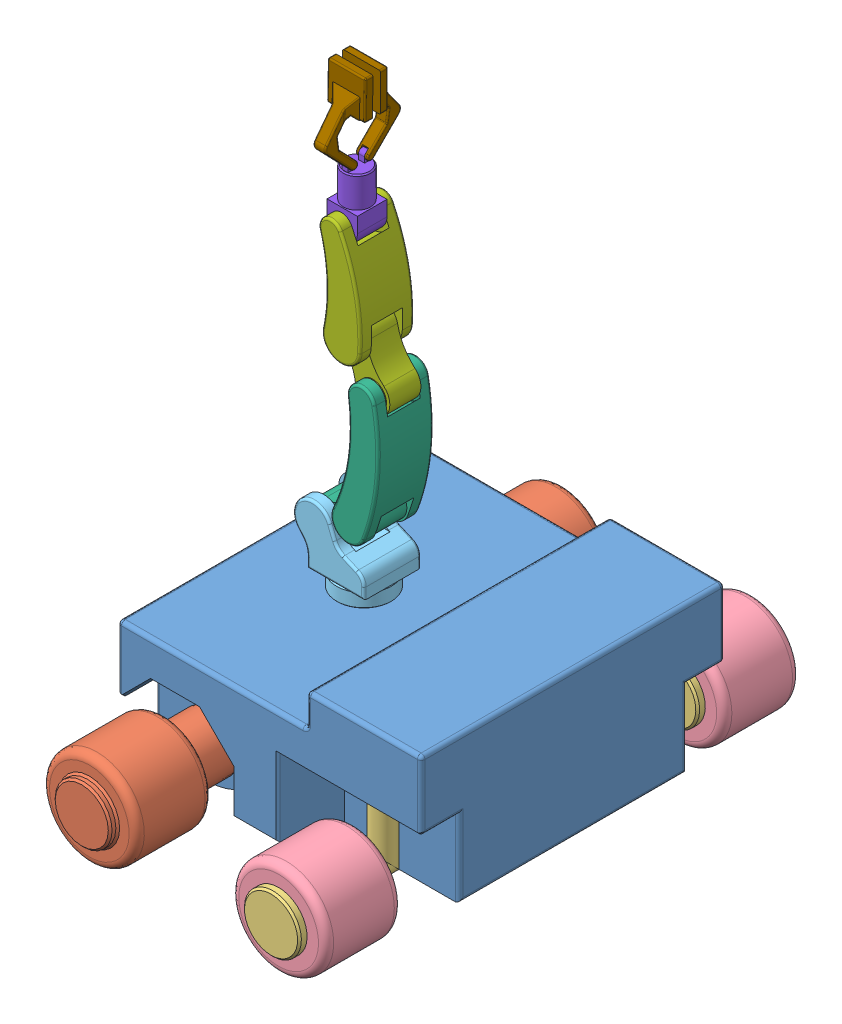
SolidWorks assembly robot_arm, configuration Default. Lengths in mm.
Overall size (2000.01 3908.66 3225).
12 component instances, 9 part files, 22 mates.
Components (placement in the parent):
- trolley-1: trolley [Default] at (-120.4409 187.5 14.5139) x (1 0 0) z (0 0 1) size (2000.01 1087.5 2000.01)
- rear_axle-1: rear_axle [Default] at (-745.4409 312.5 14.5139) x (0 0 1) z (-1 0 0) size (3225 625 625)
- pivot-1: pivot [Default] at (502.3383 312.5 -860.4861) x (1 0 0) z (0 0 1) size (375 883.47 837.5)
- pivot-2: pivot [Default] at (502.3382 312.5 889.5139) x (-1 0 0) z (0 0 -1) size (375 883.47 837.5)
- wheel-1: wheel [Default] at (502.3382 312.5 1577.0139) x (0 0 -1) z (1 0 0) size (500 625 625)
- wheel-2: wheel [Default] at (502.3383 312.5 -1047.9861) x (0 0 -1) z (1 0 0) size (500 625 625)
- rot_arm-1: rot_arm [Default] at (-497.6618 937.5 14.5139) x (0 0 -1) z (1 0 0) size (375 505 466.46)
- ext_arm-1: ext_arm [Default] at (-651.5608 1317.5 14.5139) x (0 0 1) z (-0.999861 -0.016688 0) size (365 1021.75 531.53)
- pick_arm-1: pick_arm [Default] at (-336.7474 2162.1257 14.5139) x (-0.973701 0.227829 0) z (0 0 -1) size (585.55 981.13 355)
- jaw_arm-1: jaw_arm [Default] at (-543.5155 3025.5701 14.5139) x (0 1 0) z (0 0 1) size (460 200 205)
- jaw_updated-1: jaw_updated [Default] at (-543.5155 3360.5701 -40.4861) x (1 0 0) z (0 0 1) size (250 569.16 222.09)
- jaw_updated-2: jaw_updated [Default] at (-543.5155 3360.5701 69.5139) x (-1 0 0) z (0 -0.02052 -0.999789) size (250 569.16 222.09)
Mates (geometry in assembly coordinates):
- Concentric2: concentric anti-aligned: cylinder of trolley-1 through (-745.4409 312.5 1014.5139) axis (0 0 -1) radius 100; cylinder of rear_axle-1 through (-745.4409 312.5 1627.0139) axis (0 0 1) radius 100
- Coincident1: coincident anti-aligned: plane of trolley-1 through (-120.4409 187.5 -735.4861) normal (0 0 -1); plane of rear_axle-1 through (-745.4409 500 -735.4861) normal (0 0 1)
- Coincident2: coincident anti-aligned: plane of trolley-1 through (502.3383 1008.4709 -860.4861) normal (0 -1 0); plane of pivot-1 through (502.3383 1008.4709 -860.4861) normal (0 1 0)
- Concentric3: concentric aligned: cylinder of trolley-1 through (502.3383 945.9709 -860.4861) axis (0 -1 0) radius 75; cylinder of pivot-1 through (502.3383 1008.4709 -860.4861) axis (0 -1 0) radius 75
- Coincident3: coincident aligned: circle of trolley-1; cylinder of pivot-2 through (502.3382 1008.4709 889.5139) axis (0 -1 0) radius 75
- Coincident4: coincident anti-aligned: plane of trolley-1 through (502.3382 1008.4709 889.5139) normal (0 -1 0); plane of pivot-2 through (502.3382 1008.4709 889.5139) normal (0 1 0)
- Concentric4: concentric aligned: cylinder of pivot-2 through (502.3382 312.5 1627.0139) axis (0 0 1) radius 156.25; cylinder of wheel-1 through (502.3382 312.5 1077.0139) axis (0 0 1) radius 156.25
- Coincident7: coincident anti-aligned: plane of pivot-2 through (502.3382 468.75 1577.0139) normal (0 0 -1); plane of wheel-1 through (502.3382 312.5 1577.0139) normal (0 0 1)
- Coincident8: coincident anti-aligned: plane of pivot-1 through (502.3383 468.75 -1047.9861) normal (0 0 -1); plane of wheel-2 through (502.3383 312.5 -1047.9861) normal (0 0 1)
- Concentric5: concentric anti-aligned: cylinder of pivot-1 through (502.3383 312.5 -1597.9861) axis (0 0 -1) radius 156.25; cylinder of wheel-2 through (502.3383 312.5 -1547.9861) axis (0 0 1) radius 156.25
- Coincident9: coincident anti-aligned: plane of trolley-1 through (-497.6618 1017.5 14.5139) normal (0 1 0); plane of rot_arm-1 through (-497.6618 1017.5 164.5139) normal (0 -1 0)
- Concentric6: concentric anti-aligned: cylinder of trolley-1 through (-497.6618 937.5 14.5139) axis (0 -1 0) radius 150; cylinder of rot_arm-1 through (-497.6618 1037.5 14.5139) axis (0 1 0) radius 150
- Concentric7: concentric aligned: cylinder of rot_arm-1 through (-651.5608 1317.5 247.222) axis (0 0 -1) radius 42.5; cylinder of ext_arm-1 through (-651.5608 1317.5 122.0139) axis (0 0 -1) radius 42.5
- Coincident10: coincident anti-aligned: plane of rot_arm-1 through (-776.5608 1442.5 127.0139) normal (0 0 -1); plane of ext_arm-1 through (-651.5608 1317.5 127.0139) normal (0 0 1)
- Coincident11: coincident anti-aligned: plane of ext_arm-1 through (-1043.1088 1697.3656 -92.9861) normal (0 0 1); plane of pick_arm-1 through (-336.7474 2162.1257 -92.9861) normal (0 0 -1)
- Concentric8: concentric aligned: cylinder of ext_arm-1 through (-336.7474 2162.1257 -738.6539) axis (0 0 1) radius 42.5; cylinder of pick_arm-1 through (-336.7474 2162.1257 -87.9861) axis (0 0 1) radius 42.5
- Concentric9: concentric anti-aligned: cylinder of pick_arm-1 through (-543.5155 3025.5701 -613.3546) axis (0 0 1) radius 42.5; cylinder of jaw_arm-1 through (-543.5155 3025.5701 112.0139) axis (0 0 -1) radius 42.5
- Coincident12: coincident anti-aligned: plane of pick_arm-1 through (-1132.2007 2856.4371 117.0139) normal (0 0 -1); plane of jaw_arm-1 through (-543.5155 3025.5701 117.0139) normal (0 0 1)
- Coincident13: coincident anti-aligned: plane of jaw_arm-1 through (-523.5155 3360.5701 69.5139) normal (1 0 0); plane of jaw_updated-2 through (-523.5155 3360.5701 69.5139) normal (-1 0 0)
- Coincident14: coincident anti-aligned: plane of jaw_arm-1 through (-563.5155 3360.5701 -40.4861) normal (-1 0 0); plane of jaw_updated-1 through (-563.5155 3360.5701 -40.4861) normal (1 0 0)
- Concentric12: concentric aligned: cylinder of jaw_arm-1 through (-563.5155 3360.5701 -40.4861) axis (1 0 0) radius 12.5; cylinder of jaw_updated-1 through (-618.8709 3360.5701 -40.4861) axis (1 0 0) radius 12.5
- Concentric13: concentric anti-aligned: cylinder of jaw_arm-1 through (-563.5155 3360.5701 69.5139) axis (1 0 0) radius 12.5; cylinder of jaw_updated-2 through (-468.1602 3360.5701 69.5139) axis (-1 0 0) radius 12.5
